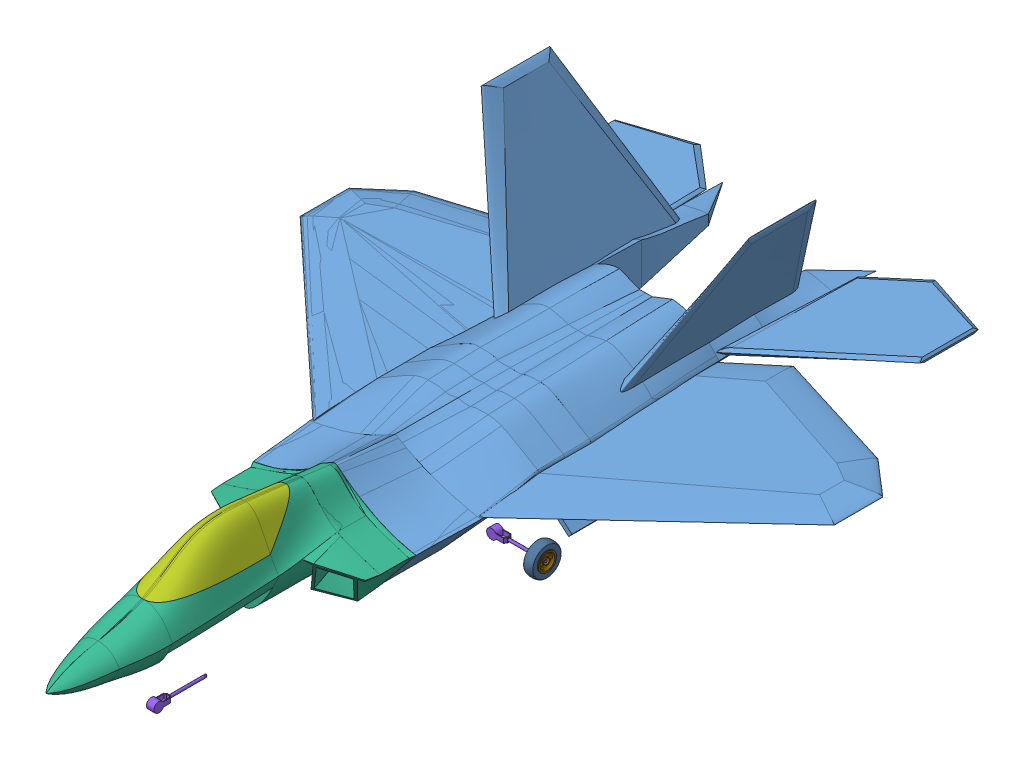
SolidWorks assembly Assem3, configuration Default. Lengths in mm.
Overall size (14299.45 6962.7 21136.23).
58 component instances, 28 part files, 17 mates.
Components (placement in the parent):
- 2nd part of jet-1: 2nd part of jet [Default] at (-285.1702 -2212.5502 14224.2057) size (14299.45 5929.29 13405.48)
- WORKING ENGINE-2: WORKING ENGINE [Default] at (-1373.4312 -2294.7495 -166.0898) x (0 0.165811 -0.986158) z (0.99995 -0.009863 -0.001658) size (3420.34 1588.24 1588.24) (flexible)
  - PART-1: PART [Default] at (-901.7861 158.0332 313.0343) x (1 0 0) z (0 -0.939868 0.341539) size (975.33 978.75 978.75)
  - Shaft-1: Shaft [Default] at (416.7367 158.0332 313.0343) x (0 0.999993 -0.003654) z (-1 0 0) size (112.5 112.5 1875)
  - Compressor Blade-1: Compressor Blade [Default] at (-333.2633 158.0332 313.0343) x (0 -0.111789 -0.993732) z (1 0 0) size (528.89 528.89 600)
  - Turbine-1: Turbine [Default] at (1184.2936 158.0333 313.0344) x (0 0.96143 0.275048) z (-1 0 0) size (750.19 750.67 455.81)
  - Propeller-1: Propeller [Default] at (-2442.0802 158.0332 313.0343) x (0 0.630821 0.775929) z (-1 0 0) size (769.59 769.73 392.18)
  - Cover 222-1: Cover 222 [Default] at (-527.0133 158.0332 313.0343) x (0 -0.987971 0.154641) z (0 -0.154641 -0.987971) size (112.5 525 112.5)
  - Compressor runner turbine 3232-4: Compressor runner turbine 3232 [Default] at (-797.8682 158.0325 313.0332) x (0 0.464405 0.885623) z (-1 0 0) size (725.21 724.31 210.38)
  - Compressor runner turbine 323244555-2: Compressor runner turbine 323244555 [Default] at (-599.4554 158.0333 313.0295) x (0 -0.003227 0.999995) z (-1 0 0) size (965.05 963.72 201.96)
  - Compressor runner turbine 323244-3: Compressor runner turbine 323244 [Default] at (644.6457 158.0408 313.0304) x (0 -0.906222 0.422801) z (-1 0 0) size (673.52 672.6 140.95)
  - Stator  2.0-1: Stator  2.0 [Default] at (-367.1881 158.0332 313.0343) x (0 -0.054088 -0.998536) z (1 0 0) size (672 675.08 60)
  - stator 2 2.0-1: stator 2 2.0 [Default] at (-273.2586 158.0333 313.0343) x (0 0.263483 0.964664) z (-1 0 0) size (478 480.05 22.53)
  - Stator 3 2.0-1: Stator 3 2.0 [Default] at (-123.2679 158.0333 313.0343) x (0 0.16716 -0.98593) z (1 0 0) size (448.16 450.05 22.53)
  - Stator 4 2.0-1: Stator 4 2.0 [Default] at (-198.268 158.0332 313.0343) x (0 -0.245046 -0.969511) z (1 0 0) size (463.08 465.05 22.53)
  - Stator 5 2.0-1: Stator 5 2.0 [Default] at (-33.2679 158.0333 313.0343) x (0 0 -1) z (1 0 0) size (433.24 435.05 22.53)
  - Stator 6 2.0-1: Stator 6 2.0 [Default] at (41.7322 158.0332 313.0343) x (0 -0.544092 -0.839026) z (1 0 0) size (410.87 412.55 22.53)
  - Stator 7 2.0-1: Stator 7 2.0 [Default] at (128.7323 158.0333 313.0343) x (0 -0.399634 -0.916675) z (1 0 0) size (388.49 390.05 22.53)
  - Stator 8 2.0-1: Stator 8 2.0 [Default] at (206.1701 158.0333 313.0343) x (0 -0.0865 -0.996252) z (1 0 0) size (347.81 349.17 21.41)
  - Centrifugal compressor 2.0-1: Centrifugal compressor 2.0 [Default] at (345.4867 158.0332 313.0343) x (0 0.994522 -0.104526) z (-1 0 0) size (654.1 654.1 83.3)
  - Centrifugal compressor 2.0-2: Centrifugal compressor 2.0 [Default] at (-532.0133 158.0332 313.0343) x (0 0.936602 0.350394) z (-1 0 0) size (654.1 654.1 83.3)
  - Turbine housing 2.0-1: Turbine housing 2.0 [Default] at (-24.883 158.0332 313.0343) x (1 0 0) z (0 0.82139 0.570367) size (603.75 989.61 989.61)
  - back of turbine-2: back of turbine [Default] at (1126.0887 158.0332 313.0343) x (0 0.999011 0.044468) z (-1 0 0) size (195.37 195.37 675)
  - cover94994309402940-1: cover94994309402940 [Default] at (66.5617 317.3605 390.3025) x (1 0 0) z (0 -0.899773 -0.436359) size (1512.13 1188.69 1188.69)
  - enging of engine-1: enging of engine [Default] at (1017.617 158.0332 313.0343) x (0 0 -1) z (1 0 0) size (1158.69 1158.69 927.21)
- Jet nose-1: Jet nose [Default] at (-285.1702 -2595.4198 14226.7457) x (-1 0 0) z (0 0 -1) size (4356.45 2567.92 7735.99)
- cabin crew-1: cabin crew [Default] at (-284.9301 -2594.8993 14226.7457) x (-1 0 0) z (0 0 -1) size (1542.38 1299.91 3949.34)
- WORKING ENGINE-3: WORKING ENGINE [Default] at (173.8925 -2294.7495 -166.0898) x (0 0.165811 -0.986158) z (0.99995 -0.009863 -0.001658) size (3420.34 1588.24 1588.24) (flexible)
  - PART-1: PART [Default] at (-901.7861 158.0332 313.0343) x (1 0 0) z (0 -0.939868 0.341539) size (975.33 978.75 978.75)
  - Shaft-1: Shaft [Default] at (416.7367 158.0332 313.0343) x (0 0.13698 -0.990574) z (-1 0 0) size (112.5 112.5 1875)
  - Compressor Blade-1: Compressor Blade [Default] at (-333.2633 158.0332 313.0343) x (0 -0.999578 -0.029038) z (1 0 0) size (528.89 528.89 600)
  - Turbine-1: Turbine [Default] at (1184.2936 158.0333 313.0343) x (0 0.407492 -0.913209) z (-1 0 0) size (750.19 750.67 455.81)
  - Propeller-1: Propeller [Default] at (-2442.0802 158.0333 313.0343) x (0 0.856913 -0.515461) z (-1 0 0) size (769.59 769.73 392.18)
  - Cover 222-1: Cover 222 [Default] at (-527.0133 158.0332 313.0343) x (0 0.014198 0.999899) z (0 -0.999899 0.014198) size (112.5 525 112.5)
  - Compressor runner turbine 3232-4: Compressor runner turbine 3232 [Default] at (-797.8682 158.032 313.0349) x (0 0.94212 -0.335275) z (-1 0 0) size (725.21 724.31 210.38)
  - Compressor runner turbine 323244555-2: Compressor runner turbine 323244555 [Default] at (-599.4554 158.0285 313.0336) x (0 0.989608 0.143793) z (-1 0 0) size (965.05 963.72 201.96)
  - Compressor runner turbine 323244-3: Compressor runner turbine 323244 [Default] at (644.6457 158.0304 313.0262) x (0 0.291188 0.956666) z (-1 0 0) size (673.52 672.6 140.95)
  - Stator  2.0-1: Stator  2.0 [Default] at (-367.1881 158.0332 313.0343) x (0 -0.054088 -0.998536) z (1 0 0) size (672 675.08 60)
  - stator 2 2.0-1: stator 2 2.0 [Default] at (-273.2586 158.0333 313.0343) x (0 0.263483 0.964664) z (-1 0 0) size (478 480.05 22.53)
  - Stator 3 2.0-1: Stator 3 2.0 [Default] at (-123.2679 158.0333 313.0343) x (0 0.16716 -0.98593) z (1 0 0) size (448.16 450.05 22.53)
  - Stator 4 2.0-1: Stator 4 2.0 [Default] at (-198.268 158.0332 313.0343) x (0 -0.245046 -0.969511) z (1 0 0) size (463.08 465.05 22.53)
  - Stator 5 2.0-1: Stator 5 2.0 [Default] at (-33.2679 158.0333 313.0343) x (0 0 -1) z (1 0 0) size (433.24 435.05 22.53)
  - Stator 6 2.0-1: Stator 6 2.0 [Default] at (41.7322 158.0332 313.0343) x (0 -0.544092 -0.839026) z (1 0 0) size (410.87 412.55 22.53)
  - Stator 7 2.0-1: Stator 7 2.0 [Default] at (128.7323 158.0333 313.0343) x (0 -0.399634 -0.916675) z (1 0 0) size (388.49 390.05 22.53)
  - Stator 8 2.0-1: Stator 8 2.0 [Default] at (206.1701 158.0333 313.0343) x (0 -0.0865 -0.996252) z (1 0 0) size (347.81 349.17 21.41)
  - Centrifugal compressor 2.0-1: Centrifugal compressor 2.0 [Default] at (345.4867 158.0332 313.0343) x (0 0.994522 -0.104526) z (-1 0 0) size (654.1 654.1 83.3)
  - Centrifugal compressor 2.0-2: Centrifugal compressor 2.0 [Default] at (-532.0133 158.0332 313.0343) x (0 0.936602 0.350394) z (-1 0 0) size (654.1 654.1 83.3)
  - Turbine housing 2.0-1: Turbine housing 2.0 [Default] at (-24.883 158.0332 313.0343) x (1 0 0) z (0 0.82139 0.570367) size (603.75 989.61 989.61)
  - back of turbine-2: back of turbine [Default] at (1126.0887 158.0332 313.0343) x (0 0.184485 -0.982835) z (-1 0 0) size (195.37 195.37 675)
  - cover94994309402940-1: cover94994309402940 [Default] at (66.5617 317.3605 390.3025) x (1 0 0) z (0 -0.899773 -0.436359) size (1512.13 1188.69 1188.69)
  - enging of engine-1: enging of engine [Default] at (1017.617 158.0332 313.0343) x (0 0 -1) z (1 0 0) size (1158.69 1158.69 927.21)
- shaft for wheel-1: shaft for wheel [Default] at (-2407.0271 -4282.845 2774.5414) x (0 0 -1) z (1 0.000118 0) size (200 264 1500)
- main wheel-1: main wheel [Default] at (-2305.0271 -4282.8309 2774.5357) x (1 0.000118 0) z (0.000085 -0.723742 -0.690071) size (266.88 487.68 487.68)
- main tire-1: main tire [Default] at (-2300.5061 -4282.8324 2774.5414) x (1 0.000118 0) z (0.000088 -0.746463 -0.665427) size (254 812.8 812.8)
- shaft for wheel-3: shaft for wheel [Default] at (1655.5071 -4282.845 2774.5414) x (0 0 1) z (-1 0.000118 0) size (200 264 1500)
- main tire-3: main tire [Default] at (1548.9861 -4282.8324 2774.5414) x (-1 0.000118 0) z (0.000088 0.746463 0.665427) size (254 812.8 812.8)
- main wheel-3: main wheel [Default] at (1553.5071 -4282.8274 2774.5391) x (-1 0.000118 0) z (0.000085 0.723742 0.690071) size (266.88 487.68 487.68)
- shaft for wheel-4: shaft for wheel [Default] at (-393.1824 -4426.9389 9830.2934) size (200 264 1500)
Mates (geometry in assembly coordinates):
- Distance2: distance = 485.625 mm aligned: plane of WORKING ENGINE-2/cover94994309402940-1 through (-780.3446 -2317.8451 -1201.8741) normal (0 0.165811 -0.986158); plane of 2nd part of jet-1 through (-285.1702 226.4435 -281.6391) normal (0 0.165811 -0.986158)
- Concentric16: concentric aligned: circle of 2nd part of jet-1; circle of WORKING ENGINE-2/cover94994309402940-1
- Tangent2: tangent: curve of 2nd part of jet-1; curve of Jet nose-1
- Coincident22: coincident anti-aligned: plane of Jet nose-1 through (6064.8298 -1695.7518 8902.7787) normal (0 1 0); plane of cabin crew-1 through (858.0699 -1695.7518 8902.7787) normal (0 -1 0)
- Coincident23: coincident anti-aligned: plane of Jet nose-1 through (6064.8298 -859.8857 7718.3481) normal (0 0.817034 0.57659); plane of cabin crew-1 through (858.0699 -859.8857 7718.3481) normal (0 -0.817034 -0.57659)
- Tangent8: tangent: curve of Jet nose-1; curve of cabin crew-1
- Distance3: distance = 485.625 mm aligned: plane of WORKING ENGINE-3/cover94994309402940-1 through (766.9791 -2317.8451 -1201.8741) normal (0 0.165811 -0.986158); plane of 2nd part of jet-1 through (-285.1702 226.4435 -281.6391) normal (0 0.165811 -0.986158)
- Concentric17: concentric anti-aligned: circle of 2nd part of jet-1; circle of WORKING ENGINE-3/cover94994309402940-1
- Parallel2: parallel aligned: line of WORKING ENGINE-2/enging of engine-1 through (-1063.9594 -2352.4731 -1980.3924) axis (0.000872 0.251125 -0.967954); line of WORKING ENGINE-3/enging of engine-1 through (483.3643 -2352.4731 -1980.3924) axis (0.000872 0.251125 -0.967954)
- Parallel4: parallel anti-aligned: line of 2nd part of jet-1 through (-285.1702 -3303.6544 6496.0017) axis (-0.99981 0.019492 0); line of Jet nose-1 through (-1547.7199 -3279.0396 6498.5417) axis (0.99981 -0.019492 0)
- Concentric31: concentric: cylinder of 2nd part of jet-1 through (-1647.0969 -2783.2234 1803.8249) axis (0 0 1) radius 30; cylinder of shaft for wheel-1 through (-1647.0969 -2783.2234 3057.6975) axis (0 0 -1) radius 30
- Distance4: distance = 374.6203 mm: plane of shaft for wheel-1 through (-1829.1907 -2895.789 2829.5414) normal (0 0 1); plane of 2nd part of jet-1 through (-285.1702 -2212.5502 3204.1617) normal (0 0 1)
- Concentric32: concentric: cylinder of shaft for wheel-1 through (-2203.0271 -4282.8209 2774.5414) axis (-1 -0.000118 0) radius 66; cylinder of main wheel-1 through (-2438.4652 -4282.8487 2774.5414) axis (1 0.000118 0) radius 72.3301
- Width5: width: plane of shaft for wheel-1 through (-2407.0271 -4282.845 2774.5414) normal (-1 -0.000118 0); plane of shaft for wheel-1 through (-2203.0271 -4282.8209 2774.5414) normal (1 0.000118 0); plane of main wheel-1 through (-2226.1216 -4282.8237 2774.5414) normal (1 0.000118 0); plane of main wheel-1 through (-2383.9327 -4282.8423 2774.5414) normal (-1 -0.000118 0)
- Concentric33: concentric aligned: circle of main wheel-1; circle of main tire-1
- Tangent19: tangent anti-aligned: cone of main wheel-1; face of main tire-1
- Coincident24: coincident: point of 2nd part of jet-1; point of Jet nose-1
